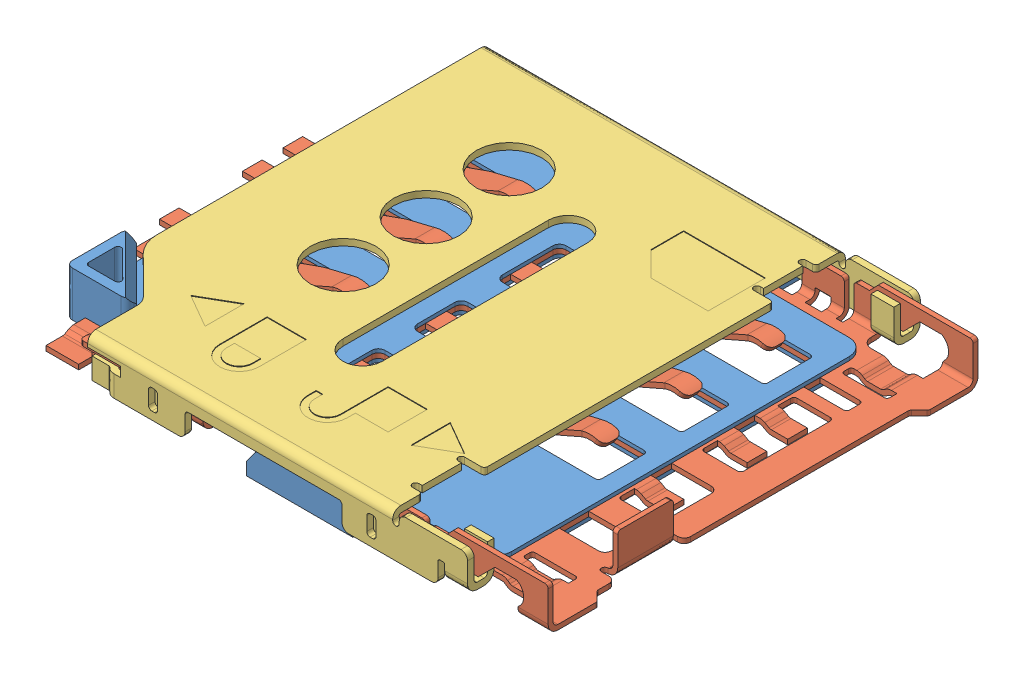
SolidWorks assembly SIM, Micro, 78800001, ASSY, configuration Default. Lengths in mm.
Overall size (16.96 1.47 13.85).
3 component instances, 3 part files, 9 mates.
Components (placement in the parent):
- SIM, Micro, 78800001, Base-1: SIM, Micro, 78800001, Base [Default] x (-1 0 0) z (0 1 0) size (13.42 13.85 1.38)
- SIM, Micro, 78800001, Contacts-1: SIM, Micro, 78800001, Contacts [Default] x (-1 0 0) z (0 1 0) size (16.96 13.69 1.47)
- SIM, Micro, 78800001, Lid-1: SIM, Micro, 78800001, Lid [Default] at (-0.1058 -0.07 0) x (-1 0 0) z (0 1 0) size (13.19 13.85 1.3)
Mates (geometry in assembly coordinates):
- Coincident1: coincident aligned: plane of SIM, Micro, 78800001, Base-1 through (0 0 0) normal (0 1 0); plane of assembly through (0 0 0) normal (0 1 0)
- Coincident2: coincident aligned: plane of SIM, Micro, 78800001, Base-1; plane of assembly through (0 0 0) normal (0 0 1)
- Coincident3: coincident anti-aligned: plane of SIM, Micro, 78800001, Base-1; plane of assembly through (0 0 0) normal (1 0 0)
- Coincident4: coincident anti-aligned: plane of SIM, Micro, 78800001, Base-1 through (-7.19 -0.075 3.5) normal (0.704901 0 -0.709306); plane of SIM, Micro, 78800001, Contacts-1 through (-7.19 -0.2051 3.5) normal (-0.704901 0 0.709306)
- Coincident5: coincident anti-aligned: plane of SIM, Micro, 78800001, Base-1 through (-7.27 -0.185 5.38) normal (0 0 1); plane of SIM, Micro, 78800001, Contacts-1 through (-7.27 -0.2051 5.38) normal (0 0 -1)
- Coincident6: coincident anti-aligned: plane of SIM, Micro, 78800001, Base-1 through (-5.78 0.075 5.18) normal (0 -1 0); plane of SIM, Micro, 78800001, Contacts-1 through (0 0.075 0) normal (0 1 0)
- Coincident7: coincident aligned: plane of SIM, Micro, 78800001, Base-1; plane of SIM, Micro, 78800001, Lid-1
- LimitAngle1: limit planar angle = 0 rad anti-aligned: plane of SIM, Micro, 78800001, Contacts-1 through (4.53 1.025 -6.485) normal (0 1 0); plane of SIM, Micro, 78800001, Lid-1 through (-6.9758 1.025 0) normal (0 -1 0)
- Concentric1: concentric aligned: circle of SIM, Micro, 78800001, Contacts-1; circle of SIM, Micro, 78800001, Lid-1
